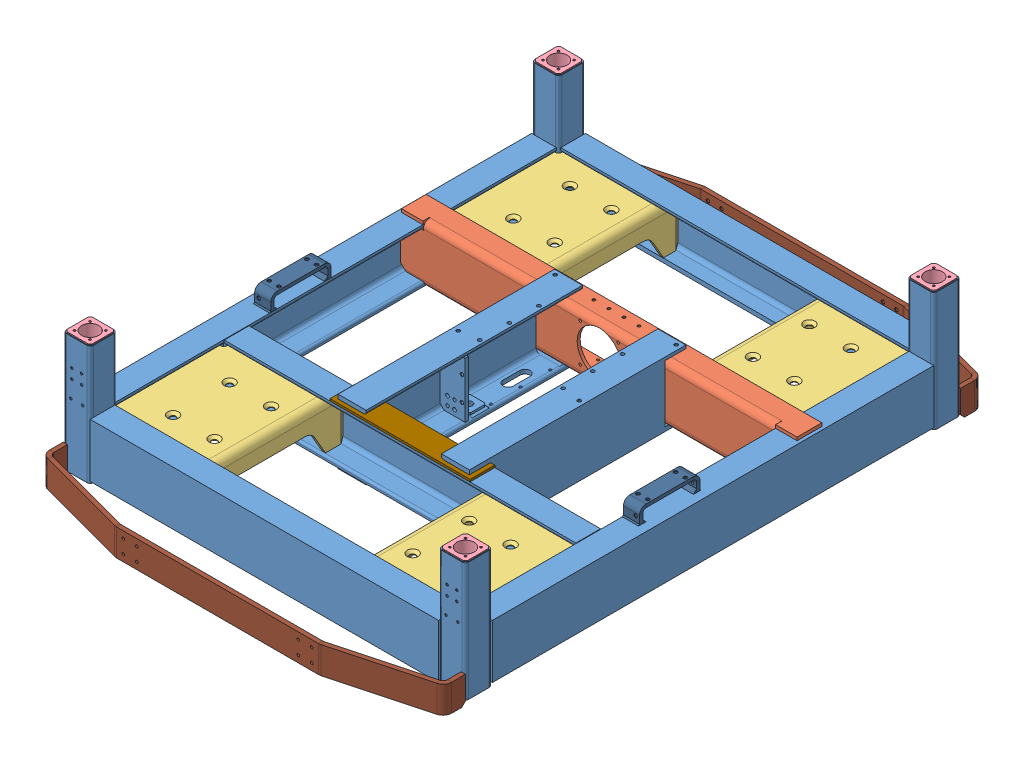
SolidWorks assembly Рама сварная в4, configuration По умолчанию. Lengths in mm.
Overall size (747 256.6 1094).
57 component instances, 11 part files, 39 mates.
Components (placement in the parent):
- Рама стенда в5 100х50-1: Рама стенда в5 100х50 [По умолчанию<Как обработанный >] at origin size (747 253.2 920)
- Балка средняя под подъемный мотор-редуктор-1: Балка средняя под подъемный мотор-редуктор [По умолчанию] at (0 94.25 -185) size (738 106.5 46)
- Колесная опора в3-1: Колесная опора в3 [Левая на гибку] at (247.5 50 -311.75) size (210 86.5 285.5)
- Колесная опора в3-2: Колесная опора в3 [Правая на гибку] at (-247.5 50 -311.75) x (-1 0 0) z (0 0 -1) size (210 86.5 285.5)
- Колесная опора в3-3: Колесная опора в3 [Левая] at (-247.5 50 311) x (-1 0 0) z (0 0 -1) size (210 84 287)
- Колесная опора в3-4: Колесная опора в3 [Правая] at (247.5 50 311) size (210 84 287)
- Державка с нижней крышкой-1: Державка с нижней крышкой [По умолчанию] at (-348.5 179.5 435) size (47 86.66 47)
  - Державка линейной направляющей-1: Державка линейной направляющей [По умолчанию] at origin size (47 80 47)
  - Крышка державки лин напр-1: Крышка державки лин напр [По умолчанию] at (0 -3 0) x (1 0 0) z (0 1 0) size (41 41 3)
  - Washer 6402_3_gost-1: Washer 6402_3_gost [Шайба 4 65Г 019 ГОСТ 6402-70] at (-14.4957 -3 14.4957) x (0.837169 0 0.546944) z (0.546944 0 -0.837169) size (6.1 1 6.1)
  - Washer 6402_3_gost-2: Washer 6402_3_gost [Шайба 4 65Г 019 ГОСТ 6402-70] at (14.4957 -3 14.4957) x (0.837169 0 0.546944) z (0.546944 0 -0.837169) size (6.1 1 6.1)
  - Washer 6402_3_gost-3: Washer 6402_3_gost [Шайба 4 65Г 019 ГОСТ 6402-70] at (14.4957 -3 -14.4957) x (0.837169 0 0.546944) z (0.546944 0 -0.837169) size (6.1 1 6.1)
  - Washer 6402_3_gost-4: Washer 6402_3_gost [Шайба 4 65Г 019 ГОСТ 6402-70] at (-14.4957 -3 -14.4957) x (0.837169 0 0.546944) z (0.546944 0 -0.837169) size (6.1 1 6.1)
  - SC GOST 17473_gost-1: SC GOST 17473_gost [Винт A.2.M4-6ex10.36.019 ГОСТ 17473-80] at (-14.4957 -6.8 14.4957) x (0 1 0) z (0 0 1) size (12.66 7.02 7.02)
  - SC GOST 17473_gost-2: SC GOST 17473_gost [Винт A.2.M4-6ex10.36.019 ГОСТ 17473-80] at (14.4957 -6.8 14.4957) x (0 1 0) z (0 0 1) size (12.66 7.02 7.02)
  - SC GOST 17473_gost-3: SC GOST 17473_gost [Винт A.2.M4-6ex10.36.019 ГОСТ 17473-80] at (14.4957 -6.8 -14.4957) x (0 1 0) z (0 0 1) size (12.66 7.02 7.02)
  - SC GOST 17473_gost-4: SC GOST 17473_gost [Винт A.2.M4-6ex10.36.019 ГОСТ 17473-80] at (-14.4957 -6.8 -14.4957) x (0 1 0) z (0 0 1) size (12.66 7.02 7.02)
- Державка с нижней крышкой-2: Державка с нижней крышкой [По умолчанию] at (348.5 179.5 435) size (47 86.66 47)
  - Державка линейной направляющей-1: Державка линейной направляющей [По умолчанию] at origin size (47 80 47)
  - Крышка державки лин напр-1: Крышка державки лин напр [По умолчанию] at (0 -3 0) x (1 0 0) z (0 1 0) size (41 41 3)
  - Washer 6402_3_gost-1: Washer 6402_3_gost [Шайба 4 65Г 019 ГОСТ 6402-70] at (-14.4957 -3 14.4957) x (0.837169 0 0.546944) z (0.546944 0 -0.837169) size (6.1 1 6.1)
  - Washer 6402_3_gost-2: Washer 6402_3_gost [Шайба 4 65Г 019 ГОСТ 6402-70] at (14.4957 -3 14.4957) x (0.837169 0 0.546944) z (0.546944 0 -0.837169) size (6.1 1 6.1)
  - Washer 6402_3_gost-3: Washer 6402_3_gost [Шайба 4 65Г 019 ГОСТ 6402-70] at (14.4957 -3 -14.4957) x (0.837169 0 0.546944) z (0.546944 0 -0.837169) size (6.1 1 6.1)
  - Washer 6402_3_gost-4: Washer 6402_3_gost [Шайба 4 65Г 019 ГОСТ 6402-70] at (-14.4957 -3 -14.4957) x (0.837169 0 0.546944) z (0.546944 0 -0.837169) size (6.1 1 6.1)
  - SC GOST 17473_gost-1: SC GOST 17473_gost [Винт A.2.M4-6ex10.36.019 ГОСТ 17473-80] at (-14.4957 -6.8 14.4957) x (0 1 0) z (0 0 1) size (12.66 7.02 7.02)
  - SC GOST 17473_gost-2: SC GOST 17473_gost [Винт A.2.M4-6ex10.36.019 ГОСТ 17473-80] at (14.4957 -6.8 14.4957) x (0 1 0) z (0 0 1) size (12.66 7.02 7.02)
  - SC GOST 17473_gost-3: SC GOST 17473_gost [Винт A.2.M4-6ex10.36.019 ГОСТ 17473-80] at (14.4957 -6.8 -14.4957) x (0 1 0) z (0 0 1) size (12.66 7.02 7.02)
  - SC GOST 17473_gost-4: SC GOST 17473_gost [Винт A.2.M4-6ex10.36.019 ГОСТ 17473-80] at (-14.4957 -6.8 -14.4957) x (0 1 0) z (0 0 1) size (12.66 7.02 7.02)
- Державка с нижней крышкой-3: Державка с нижней крышкой [По умолчанию] at (-348.5 179.5 -435) size (47 86.66 47)
  - Державка линейной направляющей-1: Державка линейной направляющей [По умолчанию] at origin size (47 80 47)
  - Крышка державки лин напр-1: Крышка державки лин напр [По умолчанию] at (0 -3 0) x (1 0 0) z (0 1 0) size (41 41 3)
  - Washer 6402_3_gost-1: Washer 6402_3_gost [Шайба 4 65Г 019 ГОСТ 6402-70] at (-14.4957 -3 14.4957) x (0.837169 0 0.546944) z (0.546944 0 -0.837169) size (6.1 1 6.1)
  - Washer 6402_3_gost-2: Washer 6402_3_gost [Шайба 4 65Г 019 ГОСТ 6402-70] at (14.4957 -3 14.4957) x (0.837169 0 0.546944) z (0.546944 0 -0.837169) size (6.1 1 6.1)
  - Washer 6402_3_gost-3: Washer 6402_3_gost [Шайба 4 65Г 019 ГОСТ 6402-70] at (14.4957 -3 -14.4957) x (0.837169 0 0.546944) z (0.546944 0 -0.837169) size (6.1 1 6.1)
  - Washer 6402_3_gost-4: Washer 6402_3_gost [Шайба 4 65Г 019 ГОСТ 6402-70] at (-14.4957 -3 -14.4957) x (0.837169 0 0.546944) z (0.546944 0 -0.837169) size (6.1 1 6.1)
  - SC GOST 17473_gost-1: SC GOST 17473_gost [Винт A.2.M4-6ex10.36.019 ГОСТ 17473-80] at (-14.4957 -6.8 14.4957) x (0 1 0) z (0 0 1) size (12.66 7.02 7.02)
  - SC GOST 17473_gost-2: SC GOST 17473_gost [Винт A.2.M4-6ex10.36.019 ГОСТ 17473-80] at (14.4957 -6.8 14.4957) x (0 1 0) z (0 0 1) size (12.66 7.02 7.02)
  - SC GOST 17473_gost-3: SC GOST 17473_gost [Винт A.2.M4-6ex10.36.019 ГОСТ 17473-80] at (14.4957 -6.8 -14.4957) x (0 1 0) z (0 0 1) size (12.66 7.02 7.02)
  - SC GOST 17473_gost-4: SC GOST 17473_gost [Винт A.2.M4-6ex10.36.019 ГОСТ 17473-80] at (-14.4957 -6.8 -14.4957) x (0 1 0) z (0 0 1) size (12.66 7.02 7.02)
- Державка с нижней крышкой-4: Державка с нижней крышкой [По умолчанию] at (348.5 179.5 -435) size (47 86.66 47)
  - Державка линейной направляющей-1: Державка линейной направляющей [По умолчанию] at origin size (47 80 47)
  - Крышка державки лин напр-1: Крышка державки лин напр [По умолчанию] at (0 -3 0) x (1 0 0) z (0 1 0) size (41 41 3)
  - Washer 6402_3_gost-1: Washer 6402_3_gost [Шайба 4 65Г 019 ГОСТ 6402-70] at (-14.4957 -3 14.4957) x (0.837169 0 0.546944) z (0.546944 0 -0.837169) size (6.1 1 6.1)
  - Washer 6402_3_gost-2: Washer 6402_3_gost [Шайба 4 65Г 019 ГОСТ 6402-70] at (14.4957 -3 14.4957) x (0.837169 0 0.546944) z (0.546944 0 -0.837169) size (6.1 1 6.1)
  - Washer 6402_3_gost-3: Washer 6402_3_gost [Шайба 4 65Г 019 ГОСТ 6402-70] at (14.4957 -3 -14.4957) x (0.837169 0 0.546944) z (0.546944 0 -0.837169) size (6.1 1 6.1)
  - Washer 6402_3_gost-4: Washer 6402_3_gost [Шайба 4 65Г 019 ГОСТ 6402-70] at (-14.4957 -3 -14.4957) x (0.837169 0 0.546944) z (0.546944 0 -0.837169) size (6.1 1 6.1)
  - SC GOST 17473_gost-1: SC GOST 17473_gost [Винт A.2.M4-6ex10.36.019 ГОСТ 17473-80] at (-14.4957 -6.8 14.4957) x (0 1 0) z (0 0 1) size (12.66 7.02 7.02)
  - SC GOST 17473_gost-2: SC GOST 17473_gost [Винт A.2.M4-6ex10.36.019 ГОСТ 17473-80] at (14.4957 -6.8 14.4957) x (0 1 0) z (0 0 1) size (12.66 7.02 7.02)
  - SC GOST 17473_gost-3: SC GOST 17473_gost [Винт A.2.M4-6ex10.36.019 ГОСТ 17473-80] at (14.4957 -6.8 -14.4957) x (0 1 0) z (0 0 1) size (12.66 7.02 7.02)
  - SC GOST 17473_gost-4: SC GOST 17473_gost [Винт A.2.M4-6ex10.36.019 ГОСТ 17473-80] at (-14.4957 -6.8 -14.4957) x (0 1 0) z (0 0 1) size (12.66 7.02 7.02)
- Подложка на опору колесную-1: Подложка на опору колесную [По умолчанию] at (-327.5 134 -174) x (1 0 0) z (0 1 0) size (170 40 6)
- Подложка на опору колесную-2: Подложка на опору колесную [По умолчанию] at (157.5 134 -174) x (1 0 0) z (0 1 0) size (170 40 6)
- Подложка под 12П швеллер-1: Подложка под 12П швеллер [По умолчанию] at (-130 141.6 208) x (1 0 0) z (0 1 0) size (260 46 4)
- подопора для колес Тенте-1: подопора для колес Тенте [со сварными швами] at (-342.5 141.6 64.5) x (0 0 -1) z (1 0 0) size (116 28.5 30)
- подопора для колес Тенте-2: подопора для колес Тенте [со сварными швами] at (342.5 141.6 64.5) x (0 0 1) z (-1 0 0) size (116 28.5 30)
- Нижнее ограждение в2-1: Нижнее ограждение в2 [По умолчанию] at (0 55 -547) x (-1 0 0) z (0 0 -1) size (747 50 87)
- Нижнее ограждение в2-2: Нижнее ограждение в2 [По умолчанию] at (0 55 547) size (747 50 87)
Mates (geometry in assembly coordinates):
- Расстояние1: distance = 25 mm anti-aligned: plane of Колесная опора в3-1 through (352.5 134 -169) normal (1 0 0); plane of Рама стенда в5 100х50-1 through (327.5 138 -460) normal (-1 0 0)
- Расстояние5: distance = 1 mm anti-aligned: plane of Колесная опора в3-1 through (156.5 120 -454.5) normal (0 0 -1); plane of Рама стенда в5 100х50-1 through (-375 56.2 -455.5) normal (0 0 1)
- Совпадение3: coincident anti-aligned: plane of Колесная опора в3-1 through (142.5 134 -169) normal (0 1 0); plane of Рама стенда в5 100х50-1 through (-375 134 -448.5) normal (0 -1 0)
- Совпадение4: coincident anti-aligned: plane of Колесная опора в3-2 through (-142.5 134 -454.5) normal (0 1 0); plane of Рама стенда в5 100х50-1 through (-375 134 -448.5) normal (0 -1 0)
- Расстояние2: distance = 25 mm anti-aligned: plane of Колесная опора в3-2 through (-352.5 134 -454.5) normal (-1 0 0); plane of Рама стенда в5 100х50-1 through (-327.5 138 -460) normal (1 0 0)
- Расстояние6: distance = 1 mm anti-aligned: plane of Колесная опора в3-2 through (-148.5 120 -454.5) normal (0 0 -1); plane of Рама стенда в5 100х50-1 through (-375 56.2 -455.5) normal (0 0 1)
- Совпадение7: coincident anti-aligned: plane of Колесная опора в3-3 through (-142.5 134 167.5) normal (0 1 0); plane of Рама стенда в5 100х50-1 through (-362 134 -460) normal (0 -1 0)
- Расстояние3: distance = 25 mm anti-aligned: plane of Колесная опора в3-3 through (-352.5 134 167.5) normal (-1 0 0); plane of Рама стенда в5 100х50-1 through (-327.5 138 -460) normal (1 0 0)
- Расстояние7: distance = 1 mm anti-aligned: plane of Колесная опора в3-3 through (-148.5 120 167.5) normal (0 0 -1); plane of Рама стенда в5 100х50-1 through (373.5 127 166.5) normal (0 0 1)
- Расстояние8: distance = 1 mm anti-aligned: plane of Колесная опора в3-4 through (156.5 120 167.5) normal (0 0 -1); plane of Рама стенда в5 100х50-1 through (373.5 127 166.5) normal (0 0 1)
- Совпадение11: coincident anti-aligned: plane of Колесная опора в3-4 through (142.5 134 454.5) normal (0 1 0); plane of Рама стенда в5 100х50-1 through (362 134 -460) normal (0 -1 0)
- Расстояние4: distance = 25 mm anti-aligned: plane of Колесная опора в3-4 through (352.5 134 454.5) normal (1 0 0); plane of Рама стенда в5 100х50-1 through (327.5 138 -460) normal (-1 0 0)
- Совпадение12: coincident anti-aligned: plane of Рама стенда в5 100х50-1 through (-367.5 257.5 454) normal (0 1 0); plane of Державка с нижней крышкой-1/Державка линейной направляющей-1 through (-325 257.5 458.5) normal (0 -1 0)
- Совпадение13: coincident anti-aligned: plane of Рама стенда в5 100х50-1 through (-329.5 237.5 413) normal (0 0 1); plane of Державка с нижней крышкой-1/Державка линейной направляющей-1 through (-370.5 257.5 413) normal (0 0 -1)
- Совпадение14: coincident anti-aligned: plane of Рама стенда в5 100х50-1 through (-370.5 237.5 416) normal (1 0 0); plane of Державка с нижней крышкой-1/Державка линейной направляющей-1 through (-370.5 257.5 457) normal (-1 0 0)
- Расстояние11: distance = 141.5 mm anti-aligned: plane of Балка средняя под подъемный мотор-редуктор-1 through (367.5 141.5 -162) normal (0 -1 0); plane of assembly through (0 0 0) normal (0 1 0)
- Совпадение19: coincident aligned: plane of Балка средняя под подъемный мотор-редуктор-1 through (0 94.25 -185) normal (1 0 0); plane of assembly through (0 0 0) normal (1 0 0)
- Расстояние12: distance = 298 mm anti-aligned: plane of Балка средняя под подъемный мотор-редуктор-1 through (367.5 41 -162) normal (0 0 1); plane of Рама стенда в5 100х50-1 through (-375 141.6 -460) normal (0 0 -1)
- Совпадение21: coincident anti-aligned: plane of Колесная опора в3-2 through (-142.5 134 -454.5) normal (0 1 0); plane of Подложка на опору колесную-1 through (-327.5 134 -214) normal (0 -1 0)
- Совпадение22: coincident anti-aligned: plane of Рама стенда в5 100х50-1 through (-327.5 138 -460) normal (1 0 0); plane of Подложка на опору колесную-1 through (-327.5 140 -174) normal (-1 0 0)
- Расстояние13: distance = 6 mm aligned: plane of Подложка на опору колесную-1 through (-327.5 140 -214) normal (0 0 -1); plane of Балка средняя под подъемный мотор-редуктор-1 through (367.5 147.5 -208) normal (0 0 -1)
- Совпадение24: coincident anti-aligned: plane of Колесная опора в3-1 through (142.5 134 -169) normal (0 1 0); plane of Подложка на опору колесную-2 through (157.5 134 -214) normal (0 -1 0)
- Совпадение25: coincident anti-aligned: plane of Рама стенда в5 100х50-1 through (327.5 138 -460) normal (-1 0 0); plane of Подложка на опору колесную-2 through (327.5 140 -174) normal (1 0 0)
- Совпадение26: coincident aligned: plane of Подложка на опору колесную-1 through (-327.5 140 -214) normal (0 0 -1); plane of Подложка на опору колесную-2 through (157.5 140 -214) normal (0 0 -1)
- Совпадение27: coincident anti-aligned: plane of Рама стенда в5 100х50-1 through (373.5 141.6 162) normal (0 1 0); plane of Подложка под 12П швеллер-1 through (-130 141.6 162) normal (0 -1 0)
- Совпадение28: coincident aligned: plane of Рама стенда в5 100х50-1 through (373.5 138 208) normal (0 0 1); plane of Подложка под 12П швеллер-1 through (-130 145.6 208) normal (0 0 1)
- Ширина1: width aligned: plane of Рама стенда в5 100х50-1 through (122 153.4 -162) normal (1 0 0); plane of Рама стенда в5 100х50-1 through (-122 153.4 -162) normal (-1 0 0); plane of Подложка под 12П швеллер-1 through (130 145.6 208) normal (1 0 0); plane of Подложка под 12П швеллер-1 through (-130 145.6 208) normal (-1 0 0)
- Совпадение29: coincident aligned: plane of подопора для колес Тенте-1 through (-327.5 164.1 20.5) normal (1 0 0); plane of Рама стенда в5 100х50-1 through (-327.5 138 -460) normal (1 0 0)
- Совпадение30: coincident anti-aligned: plane of Рама стенда в5 100х50-1 through (-373.5 141.6 -460) normal (0 1 0); plane of подопора для колес Тенте-1 through (-327.5 141.6 114.5) normal (0 -1 0)
- Расстояние14: distance = 451.5 mm anti-aligned: plane of Рама стенда в5 100х50-1 through (375 141.6 460) normal (0 0 1); plane of подопора для колес Тенте-1 through (-327.5 170.1 8.5) normal (0 0 -1)
- Совпадение32: coincident anti-aligned: plane of Рама стенда в5 100х50-1 through (373.5 141.6 -460) normal (0 1 0); plane of подопора для колес Тенте-2 through (327.5 141.6 14.5) normal (0 -1 0)
- Совпадение33: coincident aligned: plane of подопора для колес Тенте-2 through (327.5 164.1 108.5) normal (-1 0 0); plane of Рама стенда в5 100х50-1 through (327.5 138 -460) normal (-1 0 0)
- Совпадение34: coincident aligned: plane of подопора для колес Тенте-1 through (-327.5 170.1 120.5) normal (0 0 1); plane of подопора для колес Тенте-2 through (327.5 170.1 120.5) normal (0 0 1)
- Расстояние15: distance = 30 mm anti-aligned: plane of assembly through (0 0 0) normal (0 1 0); plane of Нижнее ограждение в2-1 through (-373.5 30 -485.4486) normal (0 -1 0)
- Совпадение36: coincident anti-aligned: plane of Нижнее ограждение в2-1 through (373.5 80 -460) normal (0 0 1); plane of Рама стенда в5 100х50-1 through (-329.5 257.5 -460) normal (0 0 -1)
- Совпадение37: coincident aligned: plane of Рама стенда в5 100х50-1 through (373.5 257.5 -454) normal (1 0 0); plane of Нижнее ограждение в2-1 through (373.5 80 -485.4486) normal (1 0 0)
- Расстояние16: distance = 30 mm anti-aligned: plane of Нижнее ограждение в2-2 through (373.5 30 485.4486) normal (0 -1 0); plane of assembly through (0 0 0) normal (0 1 0)
- Совпадение39: coincident anti-aligned: plane of Рама стенда в5 100х50-1 through (367.5 36.6 460) normal (0 0 1); plane of Нижнее ограждение в2-2 through (365.5 80 460) normal (0 0 -1)
- Совпадение40: coincident aligned: plane of Рама стенда в5 100х50-1 through (373.5 36.6 454) normal (1 0 0); plane of Нижнее ограждение в2-2 through (373.5 80 485.4486) normal (1 0 0)
